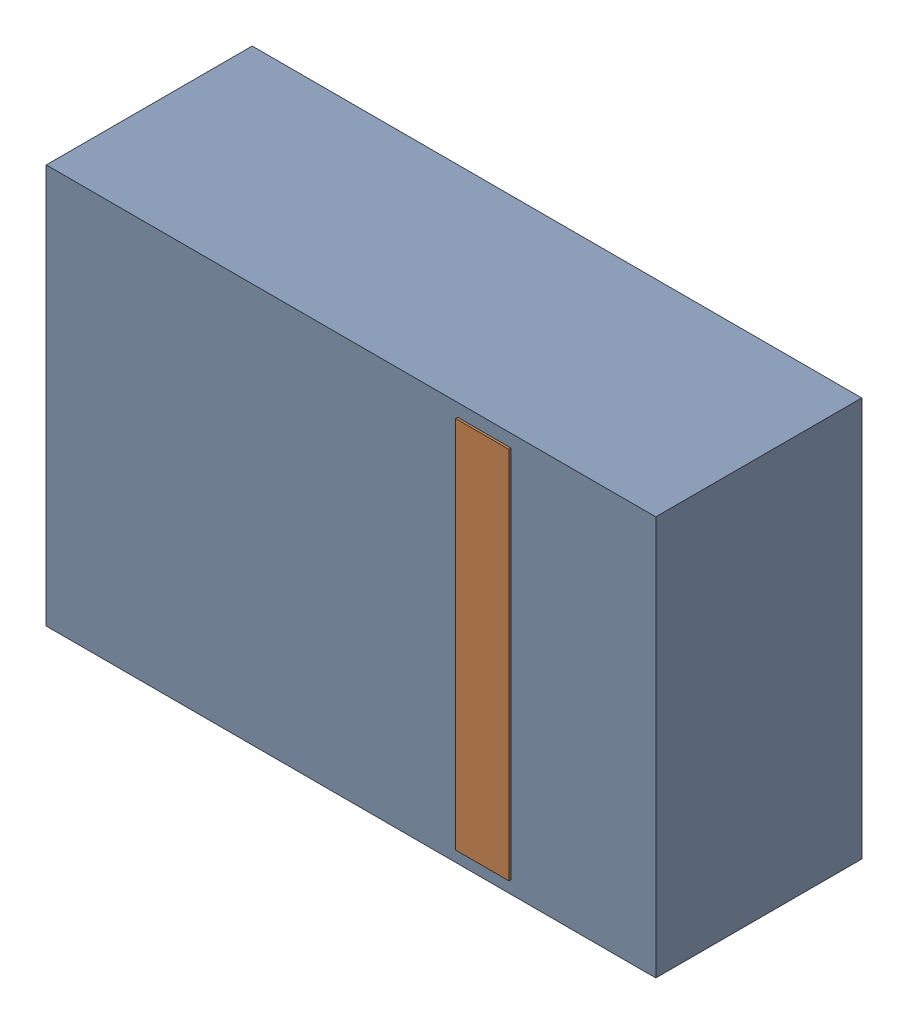
SolidWorks assembly D17, configuration Default. Lengths in mm.
Overall size (2.9 1.9 0.99).
4 component instances, 2 part files, 0 mates.
Components (placement in the parent):
- 905269392-1: 905269392 [Default] at (103.251 72.898 0) size (2.9 1.9 0.98)
  - Extruded_5-1: Extruded_5 [Default] at origin size (2.9 1.9 0.98)
- 905269800-1: 905269800 [Default] at (103.886 72.898 0.95) size (0.25 1.78 0.04)
  - Extruded_6-1: Extruded_6 [Default] at origin size (0.25 1.78 0.04)
